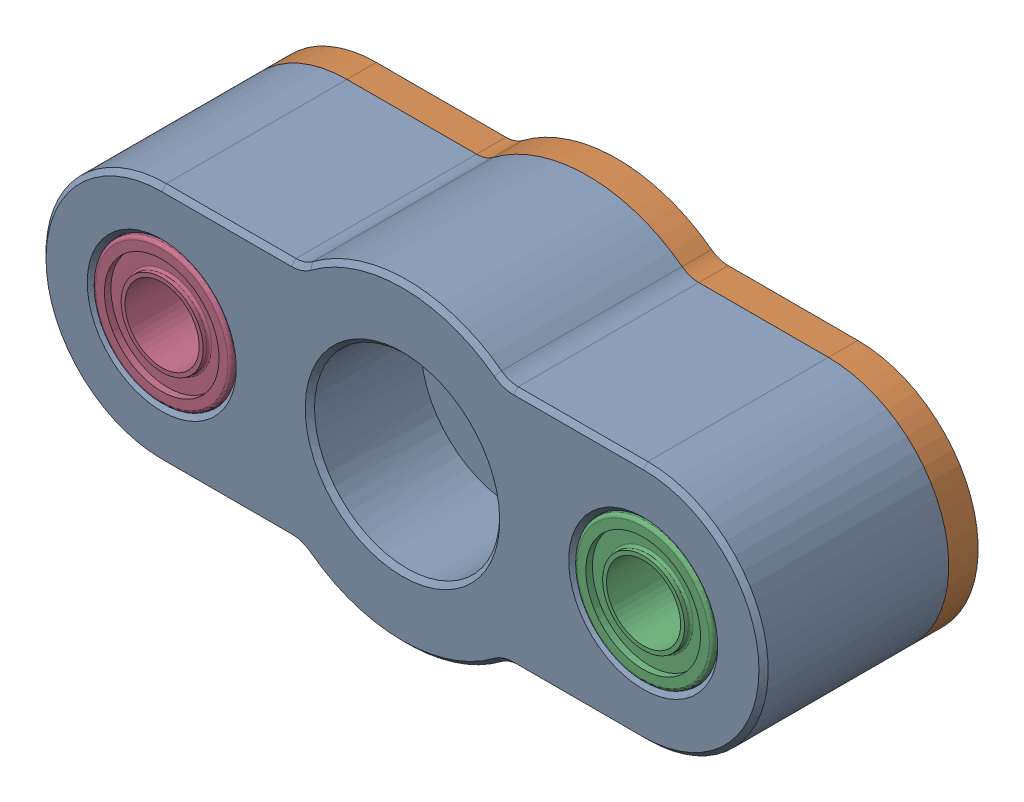
SolidWorks assembly SSDCT Spring End Asmbly, configuration Default. Lengths in mm.
Overall size (78 34 23.29).
13 component instances, 6 part files, 0 mates.
Components (placement in the parent):
- SSDCT Spring End Base-1: SSDCT Spring End Base [Default] at origin size (78 34 20)
- SSDCT Spring End Plate-1: SSDCT Spring End Plate [Default] at origin size (78 34 3.17)
- LM8SUU-1: LM8SUU [Default] at (26 0 94.675) x (0 0 -1) z (1 0 0) size (17 15 15)
- LM8SUU-2: LM8SUU [Default] at (-26 0 94.675) x (0 0 -1) z (1 0 0) size (17 15 15)
- 6659K677-1: 6659K677 [Default] at (0 0 83.175) size (16 16 8)
- 94180A333-1: 94180A333 [Default] at (-13 7.5 83.175) x (1 0 0) z (0 0 -1) size (5.56 5.56 6.4)
- 94180A333-2: 94180A333 [Default] at (-13 -7.5 83.175) x (1 0 0) z (0 0 -1) size (5.56 5.56 6.4)
- 94180A333-3: 94180A333 [Default] at (13 -7.5 83.175) x (1 0 0) z (0 0 -1) size (5.56 5.56 6.4)
- 94180A333-4: 94180A333 [Default] at (13 7.5 83.175) x (1 0 0) z (0 0 -1) size (5.56 5.56 6.4)
- M3 x 0.5 mm 14mm Length Hex Drive Flat Head Screw-1: M3 x 0.5 mm 14mm Length Hex Drive Flat Head Screw [Default] at (-13 7.5 80) x (1 0 0) z (0 0 -1) size (6 6 14.12)
- M3 x 0.5 mm 14mm Length Hex Drive Flat Head Screw-2: M3 x 0.5 mm 14mm Length Hex Drive Flat Head Screw [Default] at (-13 -7.5 80) x (1 0 0) z (0 0 -1) size (6 6 14.12)
- M3 x 0.5 mm 14mm Length Hex Drive Flat Head Screw-3: M3 x 0.5 mm 14mm Length Hex Drive Flat Head Screw [Default] at (13 -7.5 80) x (1 0 0) z (0 0 -1) size (6 6 14.12)
- M3 x 0.5 mm 14mm Length Hex Drive Flat Head Screw-4: M3 x 0.5 mm 14mm Length Hex Drive Flat Head Screw [Default] at (13 7.5 80) x (1 0 0) z (0 0 -1) size (6 6 14.12)
